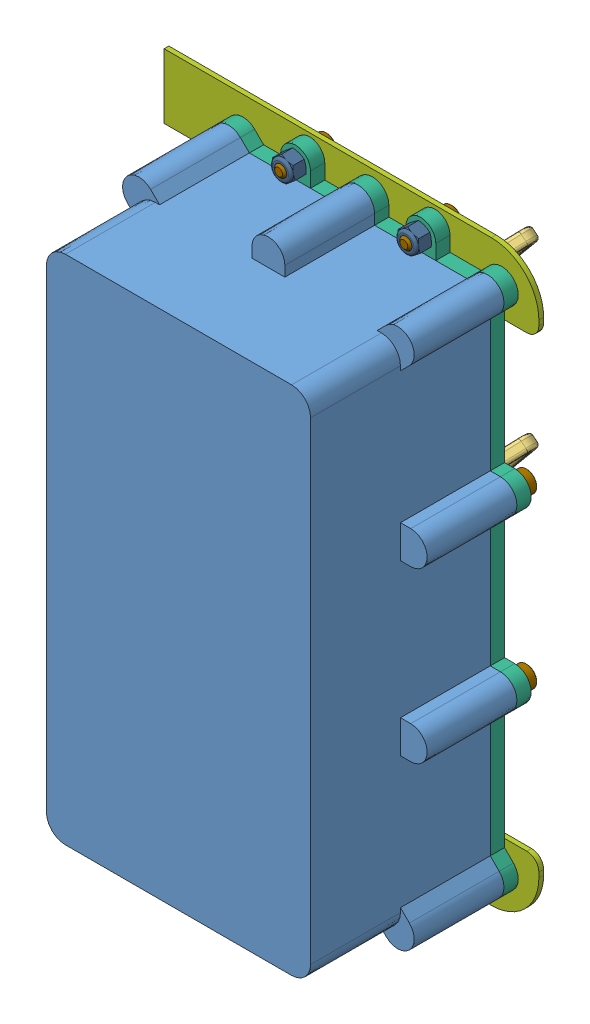
SolidWorks assembly EL-A0101-AA-TSMP + MS Assembly, configuration Default. Lengths in mm.
Overall size (125.1 193.04 109.98).
49 component instances, 13 part files, 100 mates.
Components (placement in the parent):
- EL-50020-AA-TSMP + MS Enclosure-1: EL-50020-AA-TSMP + MS Enclosure [Default] at (-164.5206 6 19.3259) size (106.02 188.57 59.98)
- EL-000XX-AA-Master Switch-1: EL-000XX-AA-Master Switch [Default] at (-126.4206 74.6871 22.3259) x (-0.7694 0.638768 0) z (0 0 -1) size (57 57 72)
- EL-000XX-AA-Master Switch-2: EL-000XX-AA-Master Switch [Default] at (-126.4206 134.4879 22.3259) x (-0.7694 0.638768 0) z (0 0 -1) size (57 57 72)
- EL-000XX-AA-Master Switch Key-1: EL-000XX-AA-Master Switch Key [Default] at (-128.3369 72.3789 -20.6741) x (-0.7694 0.638768 0) z (0 0 -1) size (9.5 46.9 50)
- EL-000XX-AA-Master Switch Key-2: EL-000XX-AA-Master Switch Key [Default] at (-128.3369 132.1797 -20.6741) x (-0.7694 0.638768 0) z (0 0 -1) size (9.5 46.9 50)
- EL-000XX-AA-Pomona Port (72930)-1: EL-000XX-AA-Pomona Port (72930) [Pomona 72930 (BLACK)] at (-99.7506 103.75 23.6312) x (-0.945625 -0.325259 0) z (0.325259 -0.945625 0) size (14.73 33.88 17.01)
- EL-000XX-AA-Pomona Port (72930)-2: EL-000XX-AA-Pomona Port (72930) [Pomona 72930 (BLACK)] at (-136.5806 23.4625 23.6312) x (0.758926 -0.651177 0) z (0.651177 0.758926 0) size (14.73 33.88 17.01)
- EL-000XX-AA-Pomona Port (72930)-3: EL-000XX-AA-Pomona Port (72930) [Pomona 72930 (RED)] at (-116.2606 23.4625 23.6312) x (-0.998131 0.061106 0) z (-0.061106 -0.998131 0) size (14.73 33.88 17.01)
- EL-500XX-AA-TSMP Cover-1: EL-500XX-AA-TSMP Cover [Default] at (-126.4206 23.4625 8.2134) x (0 0 -1) z (0 -1 0) size (13.97 71.12 30.48)
- EL-60022-AA-Enclosure Lid-1: EL-60022-AA-Enclosure Lid [Default] at (-182.2706 162.971 19.3259) size (106.02 190.75 4.76)
- EL-30021-AA-Enclosure Mounts-2: EL-30021-AA-Enclosure Mounts [Default] at (-133.0715 -19.9201 -386.9408) x (-1 0 0) z (0 0 -1) size (125.1 193.04 1.59)
- FS-Heat Set Insert, M4x7-4.7 (94180A351)-1: FS-Heat Set Insert, M4x7-4.7 (94180A351) [94180A351] at (-169.612 0.9086 21.6759) x (-0.721495 0.69242 0) z (0 0 -1) size (6.35 6.35 4.7)
- BR-Black Oxide C12.9 SHCS, M4x0.7-12 (91290A148)-1: BR-Black Oxide C12.9 SHCS, M4x0.7-12 (91290A148) [91290A148] at (-169.612 0.9086 16.9759) x (0.909602 0.41548 0) z (0 0 -1) size (7 7 16.17)
- FS-Heat Set Insert, M4x7-4.7 (94180A351)-3: FS-Heat Set Insert, M4x7-4.7 (94180A351) [94180A351] at (-126.4206 -3.4097 21.6759) x (-0.990071 -0.140566 0) z (0 0 -1) size (6.35 6.35 4.7)
- BR-Black Oxide C12.9 SHCS, M4x0.7-12 (91290A148)-3: BR-Black Oxide C12.9 SHCS, M4x0.7-12 (91290A148) [91290A148] at (-126.4206 -3.4097 16.9759) x (-1 0 0) z (0 0 -1) size (7 7 16.17)
- FS-Heat Set Insert, M4x7-4.7 (94180A351)-7: FS-Heat Set Insert, M4x7-4.7 (94180A351) [94180A351] at (-173.9303 57.181 21.6759) x (0.930432 0.366464 0) z (0 0 -1) size (6.35 6.35 4.7)
- BR-Black Oxide C12.9 SHCS, M4x0.7-12 (91290A148)-7: BR-Black Oxide C12.9 SHCS, M4x0.7-12 (91290A148) [91290A148] at (-173.9303 57.181 18.5634) x (0.651659 -0.758512 0) z (0 0 -1) size (7 7 16.17)
- BR-Black Oxide C12.9 SHCS, M4x0.7-12 (91290A148)-12: BR-Black Oxide C12.9 SHCS, M4x0.7-12 (91290A148) [91290A148] at (-147.3316 175.75 16.9759) x (0.218887 -0.97575 0) z (0 0 -1) size (7 7 16.17)
- BR-Black Oxide C12.9 SHCS, M4x0.7-12 (91290A148)-13: BR-Black Oxide C12.9 SHCS, M4x0.7-12 (91290A148) [91290A148] at (-147.3316 -5 16.9759) x (-0.84991 0.526928 0) z (0 0 -1) size (7 7 16.17)
- BR-Black Oxide C12.9 SHCS, M4x0.7-12 (91290A148)-14: BR-Black Oxide C12.9 SHCS, M4x0.7-12 (91290A148) [91290A148] at (-105.5097 -5 16.9759) x (-0.836932 0.547307 0) z (0 0 -1) size (7 7 16.17)
- FS-NYLOC C8 HX, M4x0.7-5 (90576A103)-1: FS-NYLOC C8 HX, M4x0.7-5 (90576A103) [90576A103] at (-147.3316 -5 21.8259) size (7 8.08 5)
- FS-NYLOC C8 HX, M4x0.7-5 (90576A103)-2: FS-NYLOC C8 HX, M4x0.7-5 (90576A103) [90576A103] at (-147.3316 175.75 21.8259) x (0.639392 -0.768881 0) z (0 0 1) size (7 8.08 5)
- FS-NYLOC C8 HX, M4x0.7-5 (90576A103)-3: FS-NYLOC C8 HX, M4x0.7-5 (90576A103) [90576A103] at (-105.5097 -5 21.8259) x (0.821981 0.569515 0) z (0 0 1) size (7 8.08 5)
- EL-Steel Nylon Locknut, C8, M6x1-6 (90576A115)-1: EL-Steel Nylon Locknut, C8, M6x1-6 (90576A115) [90576A115] at (-140.6545 146.3051 28.3259) x (0.999355 0.03592 0) z (0 0 1) size (10 11.55 6)
- EL-Steel Nylon Locknut, C8, M6x1-6 (90576A115)-2: EL-Steel Nylon Locknut, C8, M6x1-6 (90576A115) [90576A115] at (-112.1867 122.6707 28.3259) x (-0.960335 0.278849 0) z (0 0 1) size (10 11.55 6)
- EL-BLACK OXIDE C12.9 SHCP, M6x1-22 (91290A328)-1: EL-BLACK OXIDE C12.9 SHCP, M6x1-22 (91290A328) [91290A328] at (-112.1867 122.6707 22.5634) x (-1 0 0) z (0 0 -1) size (10 10 28.07)
- EL-BLACK OXIDE C12.9 SHCP, M6x1-22 (91290A328)-2: EL-BLACK OXIDE C12.9 SHCP, M6x1-22 (91290A328) [91290A328] at (-140.6545 146.3051 22.5634) x (-0.99792 -0.064462 0) z (0 0 -1) size (10 10 28.07)
- EL-BLACK OXIDE C12.9 SHCP, M6x1-22 (91290A328)-3: EL-BLACK OXIDE C12.9 SHCP, M6x1-22 (91290A328) [91290A328] at (-112.1867 62.8699 22.5634) x (-0.99792 -0.064462 0) z (0 0 -1) size (10 10 28.07)
- EL-BLACK OXIDE C12.9 SHCP, M6x1-22 (91290A328)-4: EL-BLACK OXIDE C12.9 SHCP, M6x1-22 (91290A328) [91290A328] at (-140.6545 86.5043 22.5634) x (-0.99792 -0.064462 0) z (0 0 -1) size (10 10 28.07)
- EL-Steel Nylon Locknut, C8, M6x1-6 (90576A115)-3: EL-Steel Nylon Locknut, C8, M6x1-6 (90576A115) [90576A115] at (-112.1867 62.8699 28.3259) x (-0.427051 0.904227 0) z (0 0 1) size (10 11.55 6)
- EL-Steel Nylon Locknut, C8, M6x1-6 (90576A115)-4: EL-Steel Nylon Locknut, C8, M6x1-6 (90576A115) [90576A115] at (-140.6545 86.5043 28.3259) x (-0.279494 0.960147 0) z (0 0 1) size (10 11.55 6)
- BR-Black Oxide C12.9 SHCS, M4x0.7-12 (91290A148)-15: BR-Black Oxide C12.9 SHCS, M4x0.7-12 (91290A148) [91290A148] at (-105.5097 175.75 16.9759) x (0.462086 -0.886835 0) z (0 0 -1) size (7 7 16.17)
- FS-NYLOC C8 HX, M4x0.7-5 (90576A103)-4: FS-NYLOC C8 HX, M4x0.7-5 (90576A103) [90576A103] at (-105.5097 175.75 21.8259) x (-0.393684 -0.919246 0) z (0 0 1) size (7 8.08 5)
- FS-PLASTIC-HEAD THUMB SCREW, M4x0.7-10 (96016A843-3: FS-PLASTIC-HEAD THUMB SCREW, M4x0.7-10 (96016A843 [Default] at (-154.3606 23.4625 13.0034) x (0 0 1) z (1 0 0) size (15.5 13 13)
- FS-PLASTIC-HEAD THUMB SCREW, M4x0.7-10 (96016A843-4: FS-PLASTIC-HEAD THUMB SCREW, M4x0.7-10 (96016A843 [Default] at (-98.4806 23.4625 13.0034) x (0 0 1) z (1 0 0) size (15.5 13 13)
- FS-Heat Set Insert, M4x7-4.7 (94180A351)-2: FS-Heat Set Insert, M4x7-4.7 (94180A351) [94180A351] at (-83.2293 0.9086 21.6759) x (0.721495 0.69242 0) z (0 0 1) size (6.35 6.35 4.7)
- BR-Black Oxide C12.9 SHCS, M4x0.7-12 (91290A148)-2: BR-Black Oxide C12.9 SHCS, M4x0.7-12 (91290A148) [91290A148] at (-83.2293 0.9086 16.9759) x (0.909602 -0.41548 0) z (0 0 -1) size (7 7 16.17)
- FS-Heat Set Insert, M4x7-4.7 (94180A351)-4: FS-Heat Set Insert, M4x7-4.7 (94180A351) [94180A351] at (-169.612 169.8414 21.6759) x (-0.721495 -0.69242 0) z (0 0 1) size (6.35 6.35 4.7)
- BR-Black Oxide C12.9 SHCS, M4x0.7-12 (91290A148)-4: BR-Black Oxide C12.9 SHCS, M4x0.7-12 (91290A148) [91290A148] at (-169.612 169.8414 16.9759) x (-0.909602 0.41548 0) z (0 0 -1) size (7 7 16.17)
- FS-Heat Set Insert, M4x7-4.7 (94180A351)-5: FS-Heat Set Insert, M4x7-4.7 (94180A351) [94180A351] at (-126.4206 174.1597 21.6759) x (0.990071 -0.140566 0) z (0 0 1) size (6.35 6.35 4.7)
- BR-Black Oxide C12.9 SHCS, M4x0.7-12 (91290A148)-5: BR-Black Oxide C12.9 SHCS, M4x0.7-12 (91290A148) [91290A148] at (-126.4206 174.1597 16.9759) x (1 0 0) z (0 0 -1) size (7 7 16.17)
- BR-Black Oxide C12.9 SHCS, M4x0.7-12 (91290A148)-6: BR-Black Oxide C12.9 SHCS, M4x0.7-12 (91290A148) [91290A148] at (-83.2293 169.8414 16.9759) x (-0.909602 -0.41548 0) z (0 0 -1) size (7 7 16.17)
- FS-Heat Set Insert, M4x7-4.7 (94180A351)-6: FS-Heat Set Insert, M4x7-4.7 (94180A351) [94180A351] at (-83.2293 169.8414 21.6759) x (0.721495 -0.69242 0) z (0 0 -1) size (6.35 6.35 4.7)
- BR-Black Oxide C12.9 SHCS, M4x0.7-12 (91290A148)-9: BR-Black Oxide C12.9 SHCS, M4x0.7-12 (91290A148) [91290A148] at (-173.9303 113.569 18.5634) x (0.651659 -0.758512 0) z (0 0 -1) size (7 7 16.17)
- FS-Heat Set Insert, M4x7-4.7 (94180A351)-9: FS-Heat Set Insert, M4x7-4.7 (94180A351) [94180A351] at (-173.9303 113.569 21.6759) x (0.930432 0.366464 0) z (0 0 -1) size (6.35 6.35 4.7)
- FS-Heat Set Insert, M4x7-4.7 (94180A351)-10: FS-Heat Set Insert, M4x7-4.7 (94180A351) [94180A351] at (-78.9109 57.181 21.6759) x (0.930432 -0.366464 0) z (0 0 1) size (6.35 6.35 4.7)
- BR-Black Oxide C12.9 SHCS, M4x0.7-12 (91290A148)-10: BR-Black Oxide C12.9 SHCS, M4x0.7-12 (91290A148) [91290A148] at (-78.9109 57.181 18.5634) x (0.651659 0.758512 0) z (0 0 -1) size (7 7 16.17)
- FS-Heat Set Insert, M4x7-4.7 (94180A351)-11: FS-Heat Set Insert, M4x7-4.7 (94180A351) [94180A351] at (-78.9109 113.569 21.6759) x (0.930432 -0.366464 0) z (0 0 1) size (6.35 6.35 4.7)
- BR-Black Oxide C12.9 SHCS, M4x0.7-12 (91290A148)-11: BR-Black Oxide C12.9 SHCS, M4x0.7-12 (91290A148) [91290A148] at (-78.9109 113.569 18.5634) x (0.651659 0.758512 0) z (0 0 -1) size (7 7 16.17)
Mates (geometry in assembly coordinates):
- Concentric12: concentric anti-aligned: cylinder of EL-000XX-AA-Master Switch-2 through (-126.4206 134.4879 19.3259) axis (0 0 -1) radius 5; cylinder of EL-000XX-AA-Master Switch Key-2 through (-126.4206 134.4879 -20.6741) axis (0 0 1) radius 4.75
- Coincident7: coincident anti-aligned: plane of EL-000XX-AA-Master Switch-2 through (-126.4206 134.4879 -10.6741) normal (0 0 -1); plane of EL-000XX-AA-Master Switch Key-2 through (-144.6836 109.359 -10.6741) normal (0 0 1)
- Parallel2: parallel: plane of EL-000XX-AA-Master Switch-2 through (-130.3193 131.3574 19.3259) normal (0.7694 -0.638768 0); line of EL-000XX-AA-Master Switch Key-2 through (-128.0152 129.4362 -11.6741) axis (-0.638768 -0.7694 0)
- Concentric18: concentric anti-aligned: cylinder of EL-800XX-BA-HVI Board-1 through (-55.9835 -25.4935 29.8055) axis (0 0 1) radius 2.1; cylinder of FS-NYLON SCREW BHCS, M4x0.7-6(94879A216)-1 through (-155.3975 139.0325 75.2021) axis (0 0 -1) radius 2
- Coincident14: coincident anti-aligned: plane of EL-800XX-BA-HVI Board-1 through (-11.47 -15.016 29.394) normal (0 0 -1); plane of FS-NYLON SCREW BHCS, M4x0.7-6(94879A216)-1 through (-155.3975 139.0325 75.2021) normal (0 0 1)
- Concentric21: concentric anti-aligned: cylinder of EL-000XX-AA-Master Switch-1 through (-126.4206 74.6871 19.3259) axis (0 0 -1) radius 5; cylinder of EL-000XX-AA-Master Switch Key-1 through (-126.4206 74.6871 -20.6741) axis (0 0 1) radius 4.75
- Parallel3: parallel anti-aligned: plane of EL-000XX-AA-Master Switch-1 through (-130.3193 71.5566 19.3259) normal (0.7694 -0.638768 0); plane of EL-000XX-AA-Master Switch Key-1 through (-129.8757 73.6564 -20.6741) normal (-0.7694 0.638768 0)
- Coincident18: coincident anti-aligned: plane of EL-000XX-AA-Master Switch-1 through (-126.4206 74.6871 -10.6741) normal (0 0 -1); plane of EL-000XX-AA-Master Switch Key-1 through (-144.6836 49.5582 -10.6741) normal (0 0 1)
- Concentric22: concentric aligned: cylinder of EL-500XX-AA-TSMP Cover-1 through (-154.3606 23.4625 10.7534) axis (0 0 -1) radius 2.4; cylinder of FS-PLASTIC-HEAD THUMB SCREW, M4x0.7-10 (96016A843-1 through (-154.3606 23.4625 5.2534) axis (0 0 -1) radius 2
- Coincident19: coincident anti-aligned: plane of EL-500XX-AA-TSMP Cover-1 through (-161.9806 13.3025 10.7534) normal (0 0 -1); plane of FS-PLASTIC-HEAD THUMB SCREW, M4x0.7-10 (96016A843-1 through (-151.1962 22.2191 10.7534) normal (0 0 1)
- Concentric23: concentric aligned: cylinder of EL-500XX-AA-TSMP Cover-1 through (-98.4806 23.4625 10.7534) axis (0 0 -1) radius 2.4; cylinder of FS-PLASTIC-HEAD THUMB SCREW, M4x0.7-10 (96016A843-2 through (-98.4806 23.4625 5.2534) axis (0 0 -1) radius 2
- Coincident20: coincident anti-aligned: plane of EL-500XX-AA-TSMP Cover-1 through (-90.8606 13.3025 10.7534) normal (0 0 -1); plane of FS-PLASTIC-HEAD THUMB SCREW, M4x0.7-10 (96016A843-2 through (-99.8556 26.5721 10.7534) normal (0 0 1)
- Coincident27: coincident anti-aligned: plane of EL-500XX-CA-TSMP Enclosure-1 through (-155.3975 139.0325 75.8259) normal (0 0 -1); plane of EL-800XX-AA-TelemHost Board-1 through (-109.9315 108.0445 75.8259) normal (0 0 1)
- Distance2: distance = 1.5875 mm: plane of EL-500XX-CA-TSMP Enclosure-1 through (-164.5206 164.75 73.3009) normal (0 -1 0); line of EL-800XX-AA-TelemHost Board-1 through (-160.4775 144.1125 75.2021) axis (1 0 0)
- Tangent2: tangent anti-aligned: torus of EL-500XX-CA-TSMP Enclosure-1 through (-164.5206 6 73.3009) normal (1 0 0); edge_curve of EL-800XX-AA-TelemHost Board-1
- Coincident35: coincident anti-aligned: plane of EL-500XX-CA-TSMP Enclosure-1 through (-164.5206 0 73.3009) normal (0 -1 0)
- Coincident38: coincident anti-aligned: plane of EL-60022-AA-Enclosure Lid-1 through (-169.612 169.8414 19.3259) normal (0 0 1); plane of EL-000XX-AA-Master Switch-1 through (-126.4206 74.6871 19.3259) normal (0 0 -1)
- Coincident39: coincident anti-aligned: plane of EL-60022-AA-Enclosure Lid-1 through (-169.612 169.8414 19.3259) normal (0 0 1); plane of EL-000XX-AA-Master Switch-2 through (-126.4206 134.4879 19.3259) normal (0 0 -1)
- Coincident40: coincident anti-aligned: plane of EL-60022-AA-Enclosure Lid-1 through (-169.612 169.8414 14.5634) normal (0 0 -1); plane of EL-500XX-AA-TSMP Cover-1 through (-141.6606 33.6225 14.5634) normal (0 0 1)
- Coincident42: coincident anti-aligned: plane of EL-60022-AA-Enclosure Lid-1 through (-169.612 169.8414 14.5634) normal (0 0 -1); plane of EL-000XX-AA-Pomona Port (72930)-2 through (-141.3772 17.8723 14.5634) normal (0 0 1)
- Coincident43: coincident anti-aligned: plane of EL-60022-AA-Enclosure Lid-1 through (-169.612 169.8414 14.5634) normal (0 0 -1); plane of EL-000XX-AA-Pomona Port (72930)-3 through (-115.8105 30.8147 14.5634) normal (0 0 1)
- Concentric39: concentric aligned: cylinder of FS-Heat Set Insert, M4x7-4.7 (94180A351)-1 through (-169.612 0.9086 19.3259) axis (0 0 -1) radius 2; cylinder of FS-NYLON SCREW BHCS, M4x0.7-6(94879A216)-1 through (-155.3975 139.0325 75.2021) axis (0 0 -1) radius 2
- Coincident50: coincident anti-aligned: plane of EL-800XX-AA-TelemHost Board-1 through (-109.9315 108.0445 75.2021) normal (0 0 -1); plane of FS-NYLON SCREW BHCS, M4x0.7-6(94879A216)-1 through (-155.3975 139.0325 75.2021) normal (0 0 1)
- Coincident51: coincident anti-aligned: plane of EL-300XX-CA-TSMP Tab-1 through (-133.0715 -19.9201 17.7384) normal (0 0 -1); plane of BR-Black Oxide C12.9 SHCS, M4x0.7-12 (91290A148)-1 through (-168.2409 -2.0931 12.9759) normal (0 0 1)
- Concentric41: concentric aligned: cylinder of EL-500XX-CA-TSMP Enclosure-1 through (-173.9303 57.181 28.3259) axis (0 0 -1) radius 3.025; cylinder of FS-Heat Set Insert, M4x7-4.7 (94180A351)-20 through (-173.9303 58.705 19.3259) axis (0 0 -1) radius 3.175
- Coincident52: coincident aligned: plane of EL-500XX-CA-TSMP Enclosure-1 through (-164.5206 6 19.3259) normal (0 0 -1); plane of FS-Heat Set Insert, M4x7-4.7 (94180A351)-20 through (-171.9307 58.7435 19.3259) normal (0 0 -1)
- Concentric42: concentric: cylinder of FS-Heat Set Insert, M4x7-4.7 (94180A351)-20 through (-173.9303 58.705 19.3259) axis (0 0 -1) radius 2; cylinder of BR-Black Oxide C12.9 SHCS, M4x0.7-12 (91290A148)-14 through (-105.5097 -5 24.9759) axis (0 0 1) radius 2
- Coincident54: coincident: plane of EL-300XX-CA-TSMP Tab-1 through (-133.0715 -19.9201 17.7384) normal (0 0 -1); plane of BR-Black Oxide C12.9 SHCS, M4x0.7-12 (91290A148)-14 through (-103.7036 -2.2381 12.9759) normal (0 0 1)
- Concentric43: concentric aligned: cylinder of EL-500XX-CA-TSMP Enclosure-1 through (-169.612 169.8414 28.3259) axis (0 0 -1) radius 3.025; cylinder of EL-300XX-CA-TSMP Tab-1 through (-169.612 169.8414 17.7384) axis (0 0 -1) radius 2.25
- Concentric44: concentric aligned: cylinder of EL-500XX-CA-TSMP Enclosure-1 through (-83.2293 0.9086 28.3259) axis (0 0 -1) radius 3.025; cylinder of EL-300XX-CA-TSMP Tab-1 through (-83.2293 0.9086 17.7384) axis (0 0 -1) radius 2.25
- Concentric45: concentric anti-aligned: cylinder of EL-300XX-CA-TSMP Tab-1 through (-99.7506 103.75 19.3259) axis (0 0 -1) radius 6.477; cylinder of EL-000XX-AA-Pomona Port (72930)-1 through (-99.7506 103.75 35.6454) axis (0 0 1) radius 5.842
- Coincident55: coincident anti-aligned: plane of EL-60022-AA-Enclosure Lid-1 through (-169.612 169.8414 14.5634) normal (0 0 -1); plane of EL-000XX-AA-Pomona Port (72930)-1 through (-102.1465 110.7155 14.5634) normal (0 0 1)
- Coincident62: coincident anti-aligned: plane of EL-500XX-CA-TSMP Enclosure-1 through (-164.5206 6 19.3259) normal (0 0 -1); plane of EL-60022-AA-Enclosure Lid-1 through (-182.2706 162.971 19.3259) normal (0 0 1)
- Coincident63: coincident aligned: plane of EL-500XX-CA-TSMP Enclosure-1 through (-164.5206 170.75 73.3009) normal (0 1 0); plane of EL-60022-AA-Enclosure Lid-1 through (-131.9206 170.75 14.5634) normal (0 1 0)
- Coincident64: coincident aligned: plane of EL-500XX-CA-TSMP Enclosure-1 through (-82.3206 6 73.3009) normal (1 0 0); plane of EL-60022-AA-Enclosure Lid-1 through (-82.3206 119.069 14.5634) normal (1 0 0)
- Coincident69: coincident anti-aligned: plane of EL-300XX-CA-TSMP Tab-1 through (-133.0715 -19.9201 19.3259) normal (0 0 1); plane of EL-60022-AA-Enclosure Lid-1 through (-169.612 169.8414 14.5634) normal (0 0 -1)
- Coincident71: coincident anti-aligned: plane of EL-60022-AA-Enclosure Lid-1 through (-169.612 169.8414 14.5634) normal (0 0 -1); plane of EL-30021-AA-Enclosure Mounts-2 through (-133.0715 -19.9201 14.5634) normal (0 0 1)
- Concentric55: concentric aligned: cylinder of EL-60022-AA-Enclosure Lid-1 through (-169.612 169.8414 14.5634) axis (0 0 -1) radius 2.25; cylinder of EL-30021-AA-Enclosure Mounts-2 through (-169.612 169.8414 12.9759) axis (0 0 -1) radius 2.25
- Concentric56: concentric aligned: cylinder of EL-60022-AA-Enclosure Lid-1 through (-83.2293 0.9086 14.5634) axis (0 0 -1) radius 2.25; cylinder of EL-30021-AA-Enclosure Mounts-2 through (-83.2293 0.9086 12.9759) axis (0 0 -1) radius 2.25
- Concentric57: concentric anti-aligned: cylinder of EL-000XX-AA-Pomona Port (72930)-2 through (-136.5806 23.4625 35.6454) axis (0 0 1) radius 7.366; cylinder of EL-60022-AA-Enclosure Lid-1 through (-136.5806 23.4625 19.3259) axis (0 0 -1) radius 6.445
- Concentric58: concentric anti-aligned: cylinder of EL-000XX-AA-Pomona Port (72930)-3 through (-116.2606 23.4625 35.6454) axis (0 0 1) radius 7.366; cylinder of EL-60022-AA-Enclosure Lid-1 through (-116.2606 23.4625 19.3259) axis (0 0 -1) radius 6.445
- Concentric59: concentric aligned: cylinder of FS-PLASTIC-HEAD THUMB SCREW, M4x0.7-10 (96016A843-2 through (-98.4806 23.4625 5.2534) axis (0 0 -1) radius 2; cylinder of EL-60022-AA-Enclosure Lid-1 through (-98.4806 23.4625 19.3259) axis (0 0 -1) radius 2.9766
- Concentric60: concentric aligned: cylinder of FS-PLASTIC-HEAD THUMB SCREW, M4x0.7-10 (96016A843-1 through (-154.3606 23.4625 5.2534) axis (0 0 -1) radius 2; cylinder of EL-60022-AA-Enclosure Lid-1 through (-154.3606 23.4625 19.3259) axis (0 0 -1) radius 2.9766
- Concentric61: concentric anti-aligned: cylinder of EL-000XX-AA-Pomona Port (72930)-1 through (-99.7506 103.75 35.6454) axis (0 0 1) radius 7.366; cylinder of EL-60022-AA-Enclosure Lid-1 through (-99.7506 103.75 19.3259) axis (0 0 -1) radius 6.445
- Concentric62: concentric aligned: cylinder of EL-500XX-CA-TSMP Enclosure-1 through (-169.612 0.9086 28.3259) axis (0 0 -1) radius 3.025; cylinder of FS-Heat Set Insert, M4x7-4.7 (94180A351)-1 through (-169.612 0.9086 19.3259) axis (0 0 -1) radius 2
- Coincident72: coincident aligned: plane of EL-500XX-CA-TSMP Enclosure-1 through (-164.5206 6 19.3259) normal (0 0 -1); plane of FS-Heat Set Insert, M4x7-4.7 (94180A351)-1 through (-168.2272 2.3516 19.3259) normal (0 0 -1)
- Concentric63: concentric anti-aligned: cylinder of EL-30021-AA-Enclosure Mounts-2 through (-169.612 0.9086 12.9759) axis (0 0 -1) radius 2.25; cylinder of BR-Black Oxide C12.9 SHCS, M4x0.7-12 (91290A148)-1 through (-169.612 0.9086 24.9759) axis (0 0 1) radius 2
- Coincident73: coincident anti-aligned: plane of EL-30021-AA-Enclosure Mounts-2 through (-133.0715 -19.9201 12.9759) normal (0 0 -1); plane of BR-Black Oxide C12.9 SHCS, M4x0.7-12 (91290A148)-1 through (-168.2409 -2.0931 12.9759) normal (0 0 1)
- Concentric64: concentric aligned: cylinder of EL-500XX-CA-TSMP Enclosure-1 through (-126.4206 -3.4097 28.3259) axis (0 0 -1) radius 3.025; cylinder of FS-Heat Set Insert, M4x7-4.7 (94180A351)-3 through (-126.4206 -3.4097 19.3259) axis (0 0 -1) radius 2
- Coincident75: coincident aligned: plane of EL-500XX-CA-TSMP Enclosure-1 through (-164.5206 6 19.3259) normal (0 0 -1); plane of FS-Heat Set Insert, M4x7-4.7 (94180A351)-3 through (-126.7018 -1.4296 19.3259) normal (0 0 -1)
- Concentric66: concentric anti-aligned: cylinder of FS-Heat Set Insert, M4x7-4.7 (94180A351)-3 through (-126.4206 -3.4097 19.3259) axis (0 0 -1) radius 2; cylinder of BR-Black Oxide C12.9 SHCS, M4x0.7-12 (91290A148)-3 through (-126.4206 -3.4097 24.9759) axis (0 0 1) radius 2
- Coincident76: coincident anti-aligned: plane of EL-30021-AA-Enclosure Mounts-2 through (-133.0715 -19.9201 12.9759) normal (0 0 -1); plane of BR-Black Oxide C12.9 SHCS, M4x0.7-12 (91290A148)-3 through (-126.4206 -0.1097 12.9759) normal (0 0 1)
- Concentric67: concentric aligned: cylinder of EL-500XX-CA-TSMP Enclosure-1 through (-173.9303 57.181 28.3259) axis (0 0 -1) radius 3.025; cylinder of FS-Heat Set Insert, M4x7-4.7 (94180A351)-7 through (-173.9303 57.181 19.3259) axis (0 0 -1) radius 2
- Coincident78: coincident aligned: plane of EL-500XX-CA-TSMP Enclosure-1 through (-164.5206 6 19.3259) normal (0 0 -1); plane of FS-Heat Set Insert, M4x7-4.7 (94180A351)-7 through (-173.1974 55.3201 19.3259) normal (0 0 -1)
- Concentric68: concentric anti-aligned: cylinder of FS-Heat Set Insert, M4x7-4.7 (94180A351)-7 through (-173.9303 57.181 19.3259) axis (0 0 -1) radius 2; cylinder of BR-Black Oxide C12.9 SHCS, M4x0.7-12 (91290A148)-7 through (-173.9303 57.181 26.5634) axis (0 0 1) radius 2
- Coincident79: coincident anti-aligned: plane of EL-60022-AA-Enclosure Lid-1 through (-169.612 169.8414 14.5634) normal (0 0 -1); plane of BR-Black Oxide C12.9 SHCS, M4x0.7-12 (91290A148)-7 through (-176.4334 55.0305 14.5634) normal (0 0 1)
- Concentric69: concentric: cylinder of EL-60022-AA-Enclosure Lid-1 through (-147.3316 175.75 19.3259) axis (0 0 1) radius 2.25; cylinder of BR-Black Oxide C12.9 SHCS, M4x0.7-8 (91290A140)-1 through (-147.3316 175.75 20.9759) axis (0 0 1) radius 2
- Coincident80: coincident anti-aligned: plane of EL-30021-AA-Enclosure Mounts-2 through (-133.0715 -19.9201 12.9759) normal (0 0 -1); plane of BR-Black Oxide C12.9 SHCS, M4x0.7-8 (91290A140)-1 through (-147.3316 179.05 12.9759) normal (0 0 1)
- Concentric70: concentric anti-aligned: cylinder of EL-30021-AA-Enclosure Mounts-2 through (-147.3316 175.75 12.9759) axis (0 0 -1) radius 2.25; cylinder of BR-Black Oxide C12.9 SHCS, M4x0.7-12 (91290A148)-12 through (-147.3316 175.75 24.9759) axis (0 0 1) radius 2
- Coincident81: coincident anti-aligned: circle of EL-30021-AA-Enclosure Mounts-2; circle of BR-Black Oxide C12.9 SHCS, M4x0.7-12 (91290A148)-12
- Coincident82: coincident anti-aligned: plane of EL-30021-AA-Enclosure Mounts-2 through (-133.0715 -19.9201 12.9759) normal (0 0 -1); plane of BR-Black Oxide C12.9 SHCS, M4x0.7-12 (91290A148)-13 through (-145.5927 -2.1953 12.9759) normal (0 0 1)
- Coincident83: coincident anti-aligned: plane of EL-30021-AA-Enclosure Mounts-2 through (-133.0715 -19.9201 12.9759) normal (0 0 -1); plane of BR-Black Oxide C12.9 SHCS, M4x0.7-12 (91290A148)-14 through (-103.7036 -2.2381 12.9759) normal (0 0 1)
- Concentric74: concentric anti-aligned: cylinder of BR-Black Oxide C12.9 SHCS, M4x0.7-12 (91290A148)-13 through (-147.3316 -5 24.9759) axis (0 0 1) radius 2; cylinder of FS-NYLOC C8 HX, M4x0.7-5 (90576A103)-1 through (-147.3316 -5 24.3259) axis (0 0 -1) radius 2
- Coincident84: coincident anti-aligned: plane of EL-60022-AA-Enclosure Lid-1 through (-169.612 169.8414 19.3259) normal (0 0 1); plane of FS-NYLOC C8 HX, M4x0.7-5 (90576A103)-1 through (-147.3316 -5 19.3259) normal (0 0 -1)
- Concentric75: concentric anti-aligned: cylinder of BR-Black Oxide C12.9 SHCS, M4x0.7-12 (91290A148)-12 through (-147.3316 175.75 24.9759) axis (0 0 1) radius 2; cylinder of FS-NYLOC C8 HX, M4x0.7-5 (90576A103)-2 through (-147.3316 175.75 24.3259) axis (0 0 -1) radius 2
- Coincident85: coincident anti-aligned: plane of EL-60022-AA-Enclosure Lid-1 through (-169.612 169.8414 19.3259) normal (0 0 1); plane of FS-NYLOC C8 HX, M4x0.7-5 (90576A103)-2 through (-147.3316 175.75 19.3259) normal (0 0 -1)
- Concentric76: concentric anti-aligned: cylinder of BR-Black Oxide C12.9 SHCS, M4x0.7-12 (91290A148)-14 through (-105.5097 -5 24.9759) axis (0 0 1) radius 2; cylinder of FS-NYLOC C8 HX, M4x0.7-5 (90576A103)-3 through (-105.5097 -5 24.3259) axis (0 0 -1) radius 2
- Coincident86: coincident anti-aligned: plane of EL-60022-AA-Enclosure Lid-1 through (-169.612 169.8414 19.3259) normal (0 0 1); plane of FS-NYLOC C8 HX, M4x0.7-5 (90576A103)-3 through (-105.5097 -5 19.3259) normal (0 0 -1)
- Concentric77: concentric anti-aligned: cylinder of EL-600XX-AA-TSMP Enclosure Acrylic Lid-1 through (-107.9206 134.4879 19.3259) axis (0 0 -1) radius 4.5; cylinder of FS-BLACK-OXIDE C12.9 SHCS, M8x1.25-30 (91290A434)-1 through (-107.9206 134.4879 44.4122) axis (0 0 1) radius 4
- Concentric80: concentric anti-aligned: cylinder of EL-000XX-AA-Master Switch-2 through (-126.4206 134.4879 -10.6741) axis (0 0 1) radius 10; cylinder of EL-60022-AA-Enclosure Lid-1 through (-126.4206 134.4879 19.3259) axis (0 0 -1) radius 11.9
- Concentric81: concentric anti-aligned: cylinder of EL-000XX-AA-Master Switch-1 through (-126.4206 74.6871 -10.6741) axis (0 0 1) radius 10; cylinder of EL-60022-AA-Enclosure Lid-1 through (-126.4206 74.6871 19.3259) axis (0 0 -1) radius 11.9
- Angle4: planar angle = 0.877901 rad anti-aligned: plane of EL-000XX-AA-Master Switch-2 through (-126.4206 134.4879 22.3259) normal (0.638768 0.7694 0); plane of EL-30021-AA-Enclosure Mounts-2 through (-195.9531 181.895 14.5634) normal (-1 0 0)
- Parallel8: parallel aligned: plane of EL-000XX-AA-Master Switch Key-1 through (-127.5675 71.7401 -20.6741) normal (0.7694 -0.638768 0); plane of EL-000XX-AA-Master Switch Key-2 through (-127.5675 131.541 -20.6741) normal (0.7694 -0.638768 0)
- Coincident90: coincident anti-aligned: plane of EL-000XX-AA-Master Switch-2 through (-126.4206 134.4879 25.3259) normal (0 0 1); plane of 90576A115_Medium-Strength Steel Nylon-Insert Locknut-1 through (-140.6545 146.3051 25.3259) normal (0 0 -1)
- Coincident91: coincident anti-aligned: plane of EL-000XX-AA-Master Switch-2 through (-126.4206 134.4879 25.3259) normal (0 0 1); plane of 90576A115_Medium-Strength Steel Nylon-Insert Locknut-2 through (-112.1867 122.6707 25.3259) normal (0 0 -1)
- Concentric88: concentric anti-aligned: cylinder of EL-60022-AA-Enclosure Lid-1 through (-112.1867 122.6707 19.3259) axis (0 0 -1) radius 3.3; cylinder of 91290A328_Alloy Steel Socket Head Screw-1 through (-112.1867 122.6707 36.5634) axis (0 0 1) radius 3
- Coincident92: coincident anti-aligned: plane of EL-60022-AA-Enclosure Lid-1 through (-169.612 169.8414 14.5634) normal (0 0 -1); plane of 91290A328_Alloy Steel Socket Head Screw-1 through (-112.1867 127.3707 14.5634) normal (0 0 1)
- Concentric89: concentric anti-aligned: cylinder of 90576A115_Medium-Strength Steel Nylon-Insert Locknut-2 through (-112.1867 122.6707 25.3259) axis (0 0 -1) radius 2.3505; cylinder of 91290A328_Alloy Steel Socket Head Screw-1 through (-112.1867 122.6707 36.5634) axis (0 0 1) radius 3
- Concentric90: concentric anti-aligned: cylinder of EL-60022-AA-Enclosure Lid-1 through (-140.6545 146.3051 19.3259) axis (0 0 -1) radius 3.3; cylinder of 91290A328_Alloy Steel Socket Head Screw-2 through (-140.6545 146.3051 36.5634) axis (0 0 1) radius 3
- Coincident93: coincident anti-aligned: plane of EL-60022-AA-Enclosure Lid-1 through (-169.612 169.8414 14.5634) normal (0 0 -1); plane of 91290A328_Alloy Steel Socket Head Screw-2 through (-140.9575 150.9953 14.5634) normal (0 0 1)
- Concentric91: concentric anti-aligned: cylinder of EL-60022-AA-Enclosure Lid-1 through (-112.1867 62.8699 19.3259) axis (0 0 -1) radius 3.3; cylinder of 91290A328_Alloy Steel Socket Head Screw-3 through (-112.1867 62.8699 36.5634) axis (0 0 1) radius 3
- Coincident94: coincident anti-aligned: plane of EL-60022-AA-Enclosure Lid-1 through (-169.612 169.8414 14.5634) normal (0 0 -1); plane of 91290A328_Alloy Steel Socket Head Screw-3 through (-112.4897 67.5601 14.5634) normal (0 0 1)
- Concentric92: concentric anti-aligned: cylinder of EL-60022-AA-Enclosure Lid-1 through (-140.6545 86.5043 19.3259) axis (0 0 -1) radius 3.3; cylinder of 91290A328_Alloy Steel Socket Head Screw-4 through (-140.6545 86.5043 36.5634) axis (0 0 1) radius 3
- Coincident95: coincident anti-aligned: plane of EL-60022-AA-Enclosure Lid-1 through (-169.612 169.8414 14.5634) normal (0 0 -1); plane of 91290A328_Alloy Steel Socket Head Screw-4 through (-140.9575 91.1945 14.5634) normal (0 0 1)
- Concentric93: concentric anti-aligned: cylinder of 91290A328_Alloy Steel Socket Head Screw-3 through (-112.1867 62.8699 36.5634) axis (0 0 1) radius 3; cylinder of 90576A115_Medium-Strength Steel Nylon-Insert Locknut-3 through (-112.1867 62.8699 31.3259) axis (0 0 -1) radius 3
- Coincident96: coincident anti-aligned: plane of EL-000XX-AA-Master Switch-1 through (-126.4206 74.6871 25.3259) normal (0 0 1); plane of 90576A115_Medium-Strength Steel Nylon-Insert Locknut-3 through (-112.1867 62.8699 25.3259) normal (0 0 -1)
- Concentric94: concentric anti-aligned: cylinder of 91290A328_Alloy Steel Socket Head Screw-4 through (-140.6545 86.5043 36.5634) axis (0 0 1) radius 3; cylinder of 90576A115_Medium-Strength Steel Nylon-Insert Locknut-4 through (-140.6545 86.5043 31.3259) axis (0 0 -1) radius 3
- Coincident97: coincident anti-aligned: plane of EL-000XX-AA-Master Switch-1 through (-126.4206 74.6871 25.3259) normal (0 0 1); plane of 90576A115_Medium-Strength Steel Nylon-Insert Locknut-4 through (-140.6545 86.5043 25.3259) normal (0 0 -1)
- Concentric95: concentric aligned: cylinder of EL-60022-AA-Enclosure Lid-1 through (-105.5097 -5 19.3259) axis (0 0 1) radius 2.25; cylinder of BR-Black Oxide C12.9 SHCS, M4x0.7-12 (91290A148)-14 through (-105.5097 -5 24.9759) axis (0 0 1) radius 2
- Concentric96: concentric anti-aligned: cylinder of EL-30021-AA-Enclosure Mounts-2 through (-105.5097 175.75 14.5634) axis (0 0 -1) radius 2.25; cylinder of BR-Black Oxide C12.9 SHCS, M4x0.7-12 (91290A148)-15 through (-105.5097 175.75 24.9759) axis (0 0 1) radius 2
- Coincident98: coincident anti-aligned: plane of EL-30021-AA-Enclosure Mounts-2 through (-133.0715 -19.9201 12.9759) normal (0 0 -1); plane of BR-Black Oxide C12.9 SHCS, M4x0.7-12 (91290A148)-15 through (-108.4363 174.2251 12.9759) normal (0 0 1)
- Concentric97: concentric anti-aligned: cylinder of EL-30021-AA-Enclosure Mounts-2 through (-147.3316 -5 14.5634) axis (0 0 -1) radius 2.25; cylinder of BR-Black Oxide C12.9 SHCS, M4x0.7-12 (91290A148)-13 through (-147.3316 -5 24.9759) axis (0 0 1) radius 2
- Concentric98: concentric anti-aligned: cylinder of BR-Black Oxide C12.9 SHCS, M4x0.7-12 (91290A148)-15 through (-105.5097 175.75 24.9759) axis (0 0 1) radius 2; cylinder of FS-NYLOC C8 HX, M4x0.7-5 (90576A103)-4 through (-105.5097 175.75 24.3259) axis (0 0 -1) radius 2
- Coincident99: coincident anti-aligned: plane of EL-60022-AA-Enclosure Lid-1 through (-169.612 169.8414 19.3259) normal (0 0 1); plane of FS-NYLOC C8 HX, M4x0.7-5 (90576A103)-4 through (-105.5097 175.75 19.3259) normal (0 0 -1)
- Concentric99: concentric aligned: cylinder of EL-500XX-AA-TSMP Cover-1 through (-154.3606 23.4625 10.7534) axis (0 0 -1) radius 2.4; cylinder of EL-60022-AA-Enclosure Lid-1 through (-154.3606 23.4625 19.3259) axis (0 0 -1) radius 2.9766
- Concentric100: concentric aligned: cylinder of EL-500XX-AA-TSMP Cover-1 through (-98.4806 23.4625 10.7534) axis (0 0 -1) radius 2.4; cylinder of EL-60022-AA-Enclosure Lid-1 through (-98.4806 23.4625 19.3259) axis (0 0 -1) radius 2.9766
- Concentric101: concentric aligned: cylinder of EL-500XX-AA-TSMP Cover-1 through (-154.3606 23.4625 10.7534) axis (0 0 -1) radius 2.4; cylinder of FS-PLASTIC-HEAD THUMB SCREW, M4x0.7-10 (96016A843-3 through (-154.3606 23.4625 5.2534) axis (0 0 -1) radius 2
- Coincident100: coincident anti-aligned: plane of EL-500XX-AA-TSMP Cover-1 through (-161.9806 13.3025 10.7534) normal (0 0 -1); plane of FS-PLASTIC-HEAD THUMB SCREW, M4x0.7-10 (96016A843-3 through (-154.3606 18.5625 10.7534) normal (0 0 1)
- Concentric102: concentric aligned: cylinder of EL-500XX-AA-TSMP Cover-1 through (-98.4806 23.4625 10.7534) axis (0 0 -1) radius 2.4; cylinder of FS-PLASTIC-HEAD THUMB SCREW, M4x0.7-10 (96016A843-4 through (-98.4806 23.4625 5.2534) axis (0 0 -1) radius 2
- Coincident101: coincident anti-aligned: plane of EL-500XX-AA-TSMP Cover-1 through (-90.8606 13.3025 10.7534) normal (0 0 -1); plane of FS-PLASTIC-HEAD THUMB SCREW, M4x0.7-10 (96016A843-4 through (-98.4806 18.5625 10.7534) normal (0 0 1)
